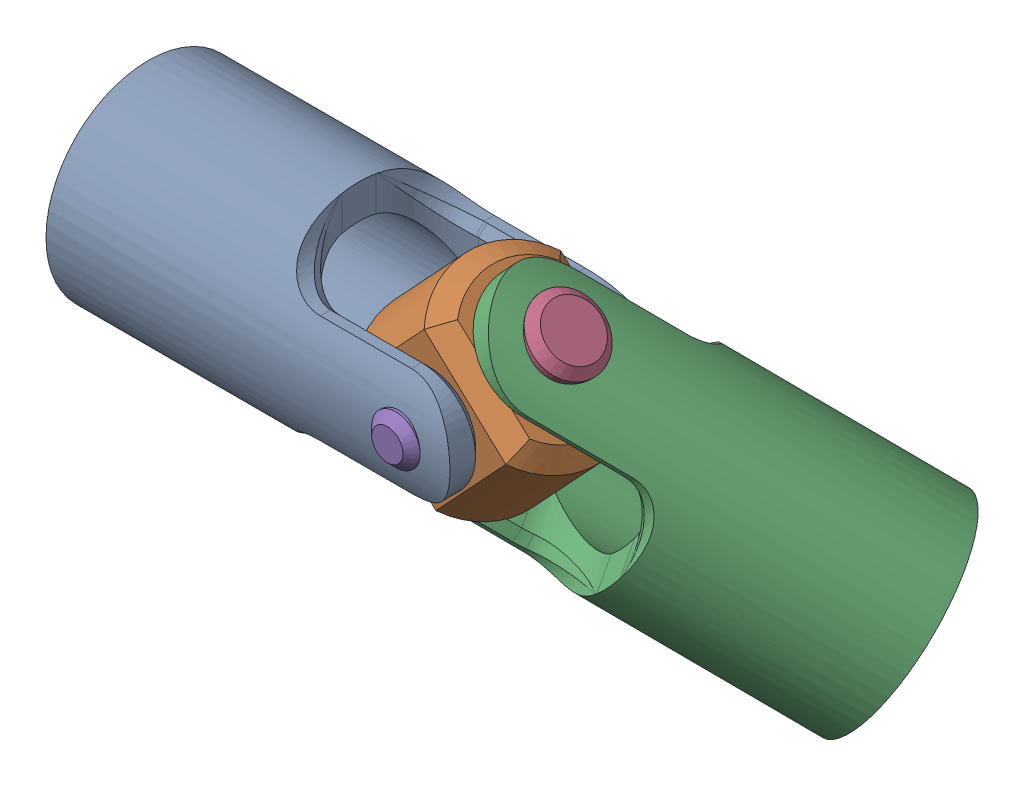
SolidWorks assembly 03_B_CSWA_Lvl9, configuration Default. Lengths in mm.
Overall size (235.03 160.4 139.1).
5 component instances, 5 part files, 10 mates.
Components (placement in the parent):
- Small-Hole-Fork-Base-1: Small-Hole-Fork-Base [Default] at origin size (142 72 72)
- Center-Block-1: Center-Block [Default] at (123 0 0) x (-0.731354 0.681998 0) z (0 0 1) size (62 48 48)
- Large-Hole-Fork-1: Large-Hole-Fork [Default] at (195.7584 -67.8483 -67.1031) x (-0.60632 0.565402 0.559193) z (0.681998 0.731354 0) size (142 72 72)
- Large-Pin-1: Large-Pin [Default] at (123 0 0) x (0.731354 -0.681998 0) z (0 0 1) size (25 78 25)
- Small-Pin-1: Small-Pin [Default] at (123 0 0) size (17 17 78)
Mates (geometry in assembly coordinates):
- Width1: width anti-aligned: plane of Center-Block-1 through (120.9822 -30.9343 24) normal (0 0 1); plane of Small-Hole-Fork-Base-1 through (120.9822 -30.9343 -24) normal (0 0 -1); plane of Center-Block-1 through (142 -36 24) normal (0 0 -1); plane of Small-Hole-Fork-Base-1 through (142 -36 -24) normal (0 0 1)
- Width2: width aligned: plane of Center-Block-1 through (106.632 -17.5525 0) normal (-0.681998 -0.731354 0); plane of Large-Hole-Fork-1 through (139.368 17.5525 0) normal (0.681998 0.731354 0); plane of Center-Block-1 through (117.3866 38.0504 -29.6084) normal (-0.681998 -0.731354 0); plane of Large-Hole-Fork-1 through (84.6507 2.9454 -29.6084) normal (0.681998 0.731354 0)
- Concentric1: concentric aligned: cylinder of Center-Block-1 through (106.632 -17.5525 0) axis (0.681998 0.731354 0) radius 12.5; cylinder of Large-Hole-Fork-1 through (98.4481 -26.3287 0) axis (0.681998 0.731354 0) radius 12.5
- Concentric2: concentric aligned: cylinder of Small-Hole-Fork-Base-1 through (123 0 -36) axis (0 0 1) radius 8.5; cylinder of Center-Block-1 through (123 0 -24) axis (0 0 1) radius 8.5
- Width3: width aligned: plane of Large-Pin-1 through (149.5979 28.5228 0) normal (0.681998 0.731354 0); plane of Center-Block-1 through (96.4021 -28.5228 0) normal (-0.681998 -0.731354 0); plane of Large-Pin-1 through (139.368 17.5525 0) normal (0.681998 0.731354 0); plane of Center-Block-1 through (106.632 -17.5525 0) normal (-0.681998 -0.731354 0)
- Concentric3: concentric anti-aligned: cylinder of Center-Block-1 through (106.632 -17.5525 0) axis (0.681998 0.731354 0) radius 12.5; cylinder of Large-Pin-1 through (149.5979 28.5228 0) axis (-0.681998 -0.731354 0) radius 12.5
- Width4: width aligned: plane of Small-Pin-1 through (123 0 39) normal (0 0 1); plane of Center-Block-1 through (123 0 -39) normal (0 0 -1); plane of Small-Pin-1 through (120.9822 -30.9343 24) normal (0 0 1); plane of Center-Block-1 through (120.9822 -30.9343 -24) normal (0 0 -1)
- Concentric4: concentric anti-aligned: cylinder of Center-Block-1 through (123 0 -24) axis (0 0 1) radius 8.5; cylinder of Small-Pin-1 through (123 0 39) axis (0 0 -1) radius 8.5
- Angle3: planar angle = 0.593412 rad aligned: plane of Center-Block-1 through (120.9822 -30.9343 24) normal (0 0 1); plane of Large-Hole-Fork-1 through (180.2037 -102.5671 -48.8643) normal (0.408968 -0.381369 0.829038)
- Angle4: planar angle = 0.750492 rad aligned: plane of Center-Block-1 through (139.368 17.5525 0) normal (0.681998 0.731354 0); plane of Small-Hole-Fork-Base-1 through (0 19 -36) normal (0 1 0)
